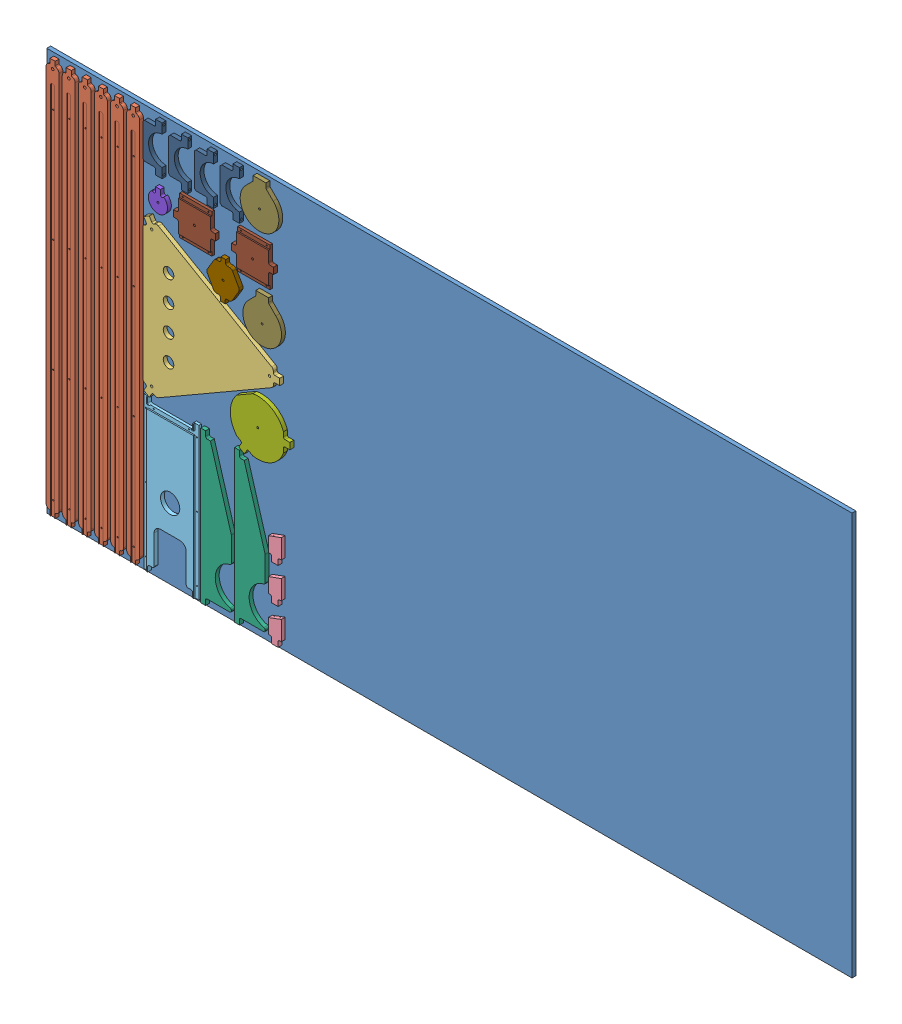
SolidWorks assembly CNCMillLayout, configuration Default. Lengths in mm.
Overall size (2500 1259.85 24).
25 component instances, 12 part files, 30 mates.
Components (placement in the parent):
- BerkenMultiplex12mm-1: BerkenMultiplex12mm [Default] at (-758.8875 1330.6733 2794.1575) size (2500 1250 12)
- TripodLegSide-1: TripodLegSide [CNCMill] at (-1978.8875 1330.6733 2806.1575) x (0 0 1) z (0 -1 0) size (12 40 1230)
- TripodSpreaderPlate-1: TripodSpreaderPlate [CNCMill] at (-1698.8875 1432.0745 2800.1575) x (0 -1 0) z (0 0 1) size (487.64 425.3 12)
- TripodSpreaderSupport-1: TripodSpreaderSupport [CNCMill] at (-1268.8875 735.6733 2806.1575) x (0 1 0) z (0 0 1) size (80 40 12)
- AltAzBase-1: AltAzBase [CNCMill] at (-1613.8875 950.6733 2806.1575) x (0 -1 0) z (0 0 1) size (470 170 12)
- AltAzSide-1: AltAzSide [CNCMill] at (-1518.8875 1165.6733 2806.1575) x (0 -1 0) z (0 0 1) size (470 95 12)
- TripodTopBase-1: TripodTopBase [CNCMill] at (-1342.0721 1275.1589 2800.1575) x (-0.866025 0.5 0) z (0 0 1) size (176.6 185 12)
- TripodTopRotDisk-1: TripodTopRotDisk [CNCMill] at (-1651.7928 1725.2637 2806.1575) size (59.5 68.54 12)
- TripodTopTopDisk-1: TripodTopTopDisk [CNCMill] at (-1449.6851 1617.1764 2800.1575) x (0.9999 -0.014121 0) z (0 0 1) size (100.83 120 12)
- TubeClampTop-1: TubeClampTop [Default] at (-1698.8875 1870.6733 2806.1575) size (60 150 12)
- TubeClampSide-1: TubeClampSide [CNCMill] at (-1358.1002 1720.6733 2806.1575) x (0 -1 0) z (0 0 1) size (120 130 12)
- AltAzSide-2: AltAzSide [CNCMill] at (-1413.8875 1165.6733 2806.1575) x (0 -1 0) z (0 0 1) size (470 95 12)
- TripodLegSide-2: TripodLegSide [CNCMill] at (-1928.8875 1330.6733 2806.1575) x (0 0 1) z (0 -1 0) size (12 40 1230)
- TripodLegSide-3: TripodLegSide [CNCMill] at (-1878.8875 1330.6733 2806.1575) x (0 0 1) z (0 -1 0) size (12 40 1230)
- TripodLegSide-4: TripodLegSide [CNCMill] at (-1828.8875 1330.6733 2806.1575) x (0 0 1) z (0 -1 0) size (12 40 1230)
- TripodLegSide-5: TripodLegSide [CNCMill] at (-1778.8875 1330.6733 2806.1575) x (0 0 1) z (0 -1 0) size (12 40 1230)
- TripodLegSide-6: TripodLegSide [CNCMill] at (-1728.8875 1330.6733 2806.1575) x (0 0 1) z (0 -1 0) size (12 40 1230)
- TubeClampSide-2: TubeClampSide [CNCMill] at (-1538.5888 1720.6733 2806.1575) x (0 -1 0) z (0 0 1) size (120 130 12)
- TripodSpreaderSupport-4: TripodSpreaderSupport [CNCMill] at (-1268.8875 845.6733 2806.1575) x (0 1 0) z (0 0 1) size (80 40 12)
- TripodSpreaderSupport-5: TripodSpreaderSupport [CNCMill] at (-1268.8875 955.6733 2806.1575) x (0 1 0) z (0 0 1) size (80 40 12)
- TubeClampTop-2: TubeClampTop [Default] at (-1618.8875 1870.6733 2806.1575) size (60 150 12)
- TubeClampTop-3: TubeClampTop [Default] at (-1538.8875 1870.6733 2806.1575) size (60 150 12)
- TubeClampTop-4: TubeClampTop [Default] at (-1458.8875 1870.6733 2806.1575) size (60 150 12)
- TubeClampDisk-1: TubeClampDisk [CNCMill] at (-1336.4109 1865.6733 2806.1575) x (0.707107 -0.707107 0) z (0 0 1) size (130.61 130.61 12)
- TubeClampDisk-2: TubeClampDisk [CNCMill] at (-1328.0683 1560.9929 2806.1575) x (0.707107 -0.707107 0) z (0 0 1) size (130.61 130.61 12)
Mates (geometry in assembly coordinates):
- Coincident1: coincident anti-aligned: plane of BerkenMultiplex12mm-1 through (-758.8875 1330.6733 2800.1575) normal (0 0 1); plane of TripodLegSide-1 through (-1998.8875 730.6733 2800.1575) normal (0 0 -1)
- Coincident2: coincident anti-aligned: plane of BerkenMultiplex12mm-1 through (-758.8875 1330.6733 2800.1575) normal (0 0 1); plane of TripodSpreaderPlate-1 through (-1698.8875 1432.0745 2800.1575) normal (0 0 -1)
- Coincident3: coincident anti-aligned: plane of BerkenMultiplex12mm-1 through (-758.8875 1330.6733 2800.1575) normal (0 0 1); plane of TripodSpreaderSupport-1 through (-1268.8875 735.6733 2800.1575) normal (0 0 -1)
- Distance2: distance = 10 mm aligned: plane of BerkenMultiplex12mm-1 through (-2008.8875 1955.6733 2800.1575) normal (-1 0 0); plane of TripodLegSide-1 through (-1998.8875 730.6733 2800.1575) normal (-1 0 0)
- Distance1: distance = 10 mm aligned: plane of TripodLegSide-1 through (-1986.8875 715.6733 2812.1575) normal (0 -1 0); plane of BerkenMultiplex12mm-1 through (-2008.8875 705.6733 2800.1575) normal (0 -1 0)
- Coincident6: coincident anti-aligned: plane of BerkenMultiplex12mm-1 through (-758.8875 1330.6733 2800.1575) normal (0 0 1); plane of AltAzBase-1 through (-1613.8875 950.6733 2800.1575) normal (0 0 -1)
- Coincident7: coincident anti-aligned: plane of BerkenMultiplex12mm-1 through (-758.8875 1330.6733 2800.1575) normal (0 0 1); plane of AltAzSide-1 through (-1413.8875 805.6733 2800.1575) normal (0 0 -1)
- Coincident8: coincident anti-aligned: plane of BerkenMultiplex12mm-1 through (-758.8875 1330.6733 2800.1575) normal (0 0 1); plane of AltAzSide-2 through (-1308.8875 805.6733 2800.1575) normal (0 0 -1)
- Coincident10: coincident aligned: plane of TripodLegSide-1 through (-1986.8875 715.6733 2812.1575) normal (0 -1 0); plane of AltAzBase-1 through (-1698.8875 715.6733 2812.1575) normal (0 -1 0)
- Distance3: distance = 310 mm aligned: plane of AltAzBase-1 through (-1698.8875 1165.6733 2812.1575) normal (-1 0 0); plane of BerkenMultiplex12mm-1 through (-2008.8875 1955.6733 2800.1575) normal (-1 0 0)
- Distance4: distance = 10 mm anti-aligned: plane of AltAzBase-1 through (-1528.8875 1165.6733 2812.1575) normal (1 0 0); plane of AltAzSide-1 through (-1518.8875 1165.6733 2812.1575) normal (-1 0 0)
- Coincident13: coincident aligned: plane of AltAzBase-1 through (-1528.8875 715.6733 2812.1575) normal (0 -1 0); plane of AltAzSide-1 through (-1518.8875 715.6733 2800.1575) normal (0 -1 0)
- Coincident15: coincident anti-aligned: plane of BerkenMultiplex12mm-1 through (-758.8875 1330.6733 2800.1575) normal (0 0 1); plane of TripodTopBase-1 through (-1342.0721 1275.1589 2800.1575) normal (0 0 -1)
- Coincident16: coincident anti-aligned: plane of BerkenMultiplex12mm-1 through (-758.8875 1330.6733 2800.1575) normal (0 0 1); plane of TripodTopRotDisk-1 through (-1651.7928 1725.2637 2800.1575) normal (0 0 -1)
- Coincident17: coincident anti-aligned: plane of BerkenMultiplex12mm-1 through (-758.8875 1330.6733 2800.1575) normal (0 0 1); plane of TripodTopTopDisk-1 through (-1449.6851 1617.1764 2800.1575) normal (0 0 -1)
- Coincident18: coincident anti-aligned: plane of BerkenMultiplex12mm-1 through (-758.8875 1330.6733 2800.1575) normal (0 0 1); plane of TubeClampSide-1 through (-1358.1002 1720.6733 2800.1575) normal (0 0 -1)
- Coincident19: coincident anti-aligned: plane of BerkenMultiplex12mm-1 through (-758.8875 1330.6733 2800.1575) normal (0 0 1); plane of TubeClampTop-1 through (-1635.8875 1870.6733 2800.1575) normal (0 0 -1)
- Coincident22: coincident aligned: plane of TripodSpreaderPlate-1 through (-1698.8875 1641.0745 2812.1575) normal (-1 0 0); plane of AltAzBase-1 through (-1698.8875 1165.6733 2812.1575) normal (-1 0 0)
- Coincident23: coincident anti-aligned: plane of BerkenMultiplex12mm-1 through (-758.8875 1330.6733 2800.1575) normal (0 0 1); plane of TubeClampSide-2 through (-1538.5888 1720.6733 2800.1575) normal (0 0 -1)
- Coincident24: coincident aligned: plane of TubeClampSide-1 through (-1308.1002 1780.6733 2812.1575) normal (0 1 0); plane of TubeClampSide-2 through (-1488.5888 1780.6733 2812.1575) normal (0 1 0)
- Distance5: distance = 175 mm aligned: plane of BerkenMultiplex12mm-1 through (-2008.8875 1955.6733 2800.1575) normal (0 1 0); plane of TubeClampSide-1 through (-1308.1002 1780.6733 2812.1575) normal (0 1 0)
- Distance7: distance = 10 mm anti-aligned: plane of TripodSpreaderPlate-1 through (-1655.5862 1198.0745 2812.1575) normal (0.5 -0.866025 0); plane of TripodTopBase-1 through (-1406.9468 1330.0795 2800.1565) normal (-0.5 0.866025 0)
- Coincident31: coincident: line of TripodSpreaderPlate-1 through (-1698.8875 1635.301 2812.1575) axis (0 -1 0); plane of TubeClampTop-1 through (-1698.8875 1815.6733 2812.1575) normal (-1 0 0)
- Coincident34: coincident aligned: plane of AltAzSide-1 through (-1518.8875 715.6733 2800.1575) normal (0 -1 0); plane of AltAzSide-2 through (-1413.8875 715.6733 2800.1575) normal (0 -1 0)
- Coincident35: coincident aligned: plane of TripodSpreaderSupport-1 through (-1298.8875 715.6733 2800.1575) normal (0 -1 0); plane of AltAzSide-2 through (-1413.8875 715.6733 2800.1575) normal (0 -1 0)
- Distance9: distance = 10 mm anti-aligned: plane of AltAzSide-2 through (-1318.8875 864.8341 2812.1575) normal (1 0 0); plane of TripodSpreaderSupport-1 through (-1308.8875 735.6733 2812.1575) normal (-1 0 0)
- Distance10: distance = 10 mm anti-aligned: plane of AltAzSide-2 through (-1413.8875 1165.6733 2812.1575) normal (-1 0 0); plane of AltAzSide-1 through (-1423.8875 864.8341 2812.1575) normal (1 0 0)
- Coincident38: coincident anti-aligned: plane of BerkenMultiplex12mm-1 through (-758.8875 1330.6733 2800.1575) normal (0 0 1); plane of TubeClampDisk-1 through (-1336.4109 1865.6733 2800.1575) normal (0 0 -1)
- Coincident39: coincident aligned: plane of TripodLegSide-1 through (-1986.8875 1945.6733 2812.1575) normal (0 1 0); plane of TubeClampDisk-1 through (-1316.558 1945.6733 2812.1575) normal (0 1 0)
- Coincident40: coincident anti-aligned: plane of BerkenMultiplex12mm-1 through (-758.8875 1330.6733 2800.1575) normal (0 0 1); plane of TubeClampDisk-2 through (-1328.0683 1560.9929 2800.1575) normal (0 0 -1)
